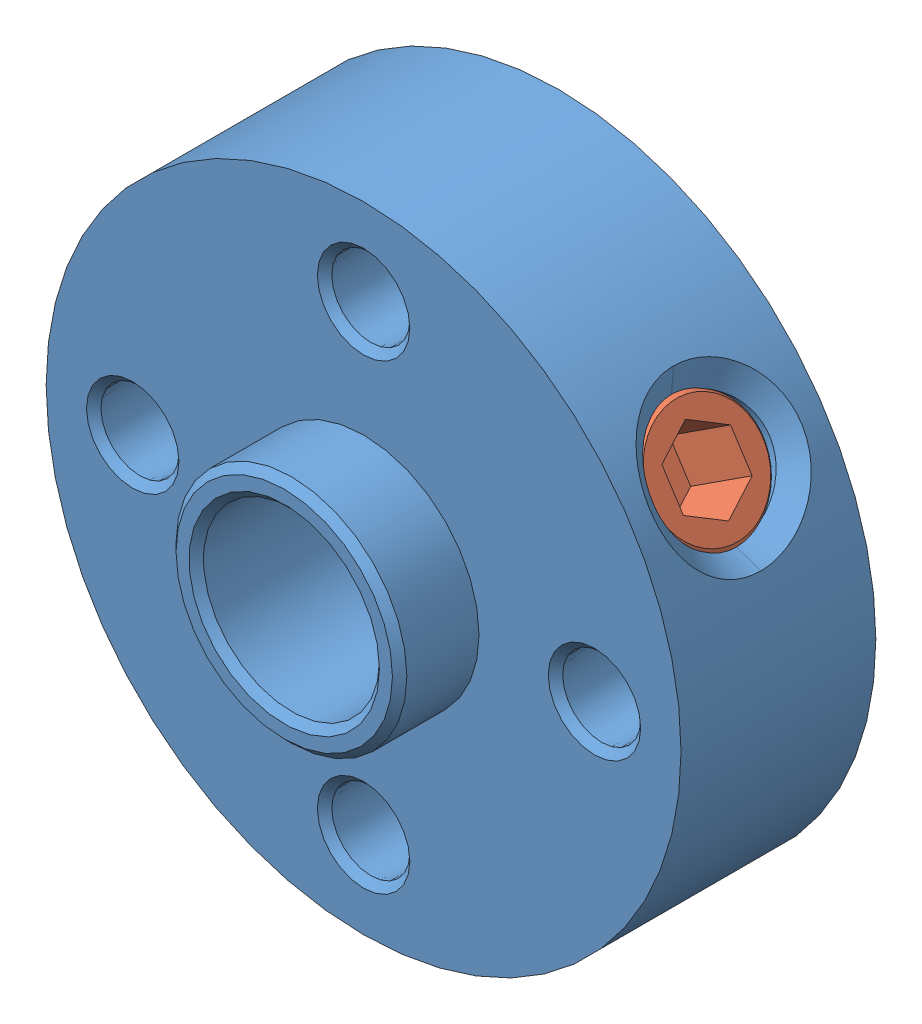
SolidWorks assembly Tetrix Motor Hub, configuration Default. Lengths in mm.
Overall size (22 22 9.5).
2 component instances, 2 part files, 0 mates.
Components (placement in the parent):
- Tetrix Motor Hub Body-1: Tetrix Motor Hub Body [Default] at origin size (22 22 9.5)
- Tetrix Motor Hub Set Screw-1: Tetrix Motor Hub Set Screw [Default] at (8.5735 5.5677 -3.325) x (-0.544639 0.838671 0) z (0 0 1) size (4.83 7.94 4.83)
